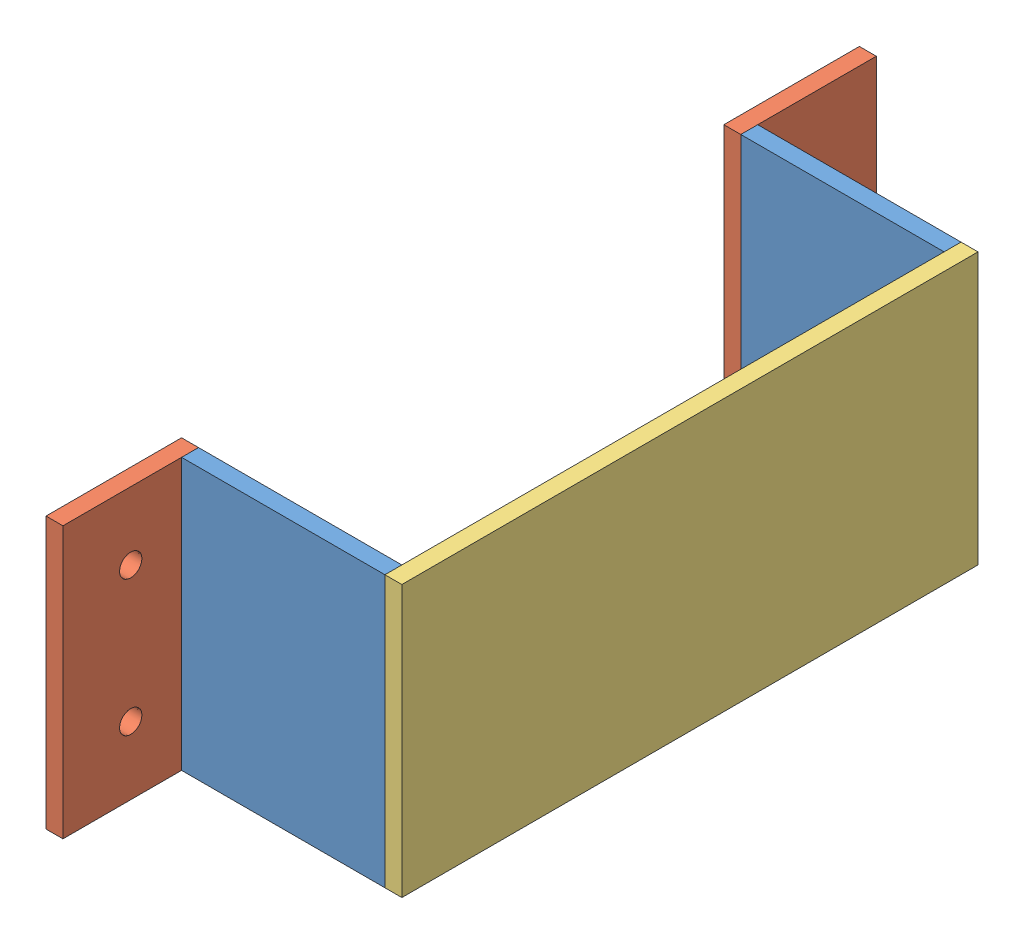
SolidWorks assembly Battery Box Assembled, configuration Default. Lengths in mm.
Overall size (44.45 50.8 152.4).
5 component instances, 3 part files, 13 mates.
Components (placement in the parent):
- Side Bat Box-1: Side Bat Box [Default] at (1.943 29.1446 44.5969) size (38.1 50.8 3.17)
- To Wall Bat Box-1: To Wall Bat Box [Default] at (-17.107 29.1446 57.2969) x (0 0 -1) z (-1 0 0) size (25.4 50.8 3.17)
- Top-1: Top [Default] at (20.993 29.1446 -6.2031) x (0 0 -1) z (1 0 0) size (107.95 50.8 3.17)
- Side Bat Box-2: Side Bat Box [Default] at (1.943 29.1446 -60.1781) size (38.1 50.8 3.17)
- To Wall Bat Box-2: To Wall Bat Box [Default] at (-20.282 29.1446 -69.7031) x (0 0 -1) z (1 0 0) size (25.4 50.8 3.17)
Mates (geometry in assembly coordinates):
- Coincident1: coincident aligned: plane of Top-1 through (24.168 54.5446 47.7719) normal (0 1 0); plane of Side Bat Box-2 through (-17.107 54.5446 -57.0031) normal (0 1 0)
- Coincident2: coincident: plane of Side Bat Box-2 through (-17.107 54.5446 -57.0031) normal (0 1 0); plane of To Wall Bat Box-2 through (-17.107 54.5446 -57.0031) normal (0 1 0)
- Coincident3: coincident: plane of Side Bat Box-1 through (-17.107 54.5446 47.7719) normal (0 1 0); line of Top-1 through (24.168 54.5446 -60.1781) axis (0 0 1)
- Coincident4: coincident: plane of Side Bat Box-1 through (-17.107 54.5446 47.7719) normal (0 1 0); plane of To Wall Bat Box-1 through (-20.282 54.5446 69.9969) normal (0 1 0)
- Coincident5: coincident: plane of Side Bat Box-1 through (1.943 29.1446 44.5969) normal (0 0 -1); plane of To Wall Bat Box-1 through (-20.282 54.5446 44.5969) normal (0 0 -1)
- Coincident6: coincident anti-aligned: plane of Side Bat Box-1 through (-17.107 3.7446 47.7719) normal (-1 0 0); plane of To Wall Bat Box-1 through (-17.107 29.1446 57.2969) normal (1 0 0)
- Coincident7: coincident anti-aligned: plane of Side Bat Box-1 through (20.993 3.7446 47.7719) normal (1 0 0); plane of Top-1 through (20.993 29.1446 -6.2031) normal (-1 0 0)
- Coincident8: coincident aligned: plane of Side Bat Box-1 through (1.943 29.1446 47.7719) normal (0 0 1); plane of Top-1 through (24.168 3.7446 47.7719) normal (0 0 1)
- Perpendicular1: perpendicular: plane of Side Bat Box-1 through (-17.107 54.5446 47.7719) normal (0 1 0); plane of Top-1 through (20.993 29.1446 -6.2031) normal (-1 0 0)
- Coincident9: coincident anti-aligned: plane of Top-1 through (20.993 29.1446 -6.2031) normal (-1 0 0); plane of Side Bat Box-2 through (20.993 3.7446 -57.0031) normal (1 0 0)
- Coincident10: coincident aligned: plane of Top-1 through (24.168 3.7446 -60.1781) normal (0 0 -1); plane of Side Bat Box-2 through (1.943 29.1446 -60.1781) normal (0 0 -1)
- Coincident11: coincident: plane of Side Bat Box-2 through (-17.107 3.7446 -57.0031) normal (-1 0 0); plane of To Wall Bat Box-2 through (-17.107 29.1446 -69.7031) normal (1 0 0)
- Coincident12: coincident aligned: plane of Side Bat Box-2 through (1.943 29.1446 -57.0031) normal (0 0 1); plane of To Wall Bat Box-2 through (-17.107 3.7446 -57.0031) normal (0 0 1)
